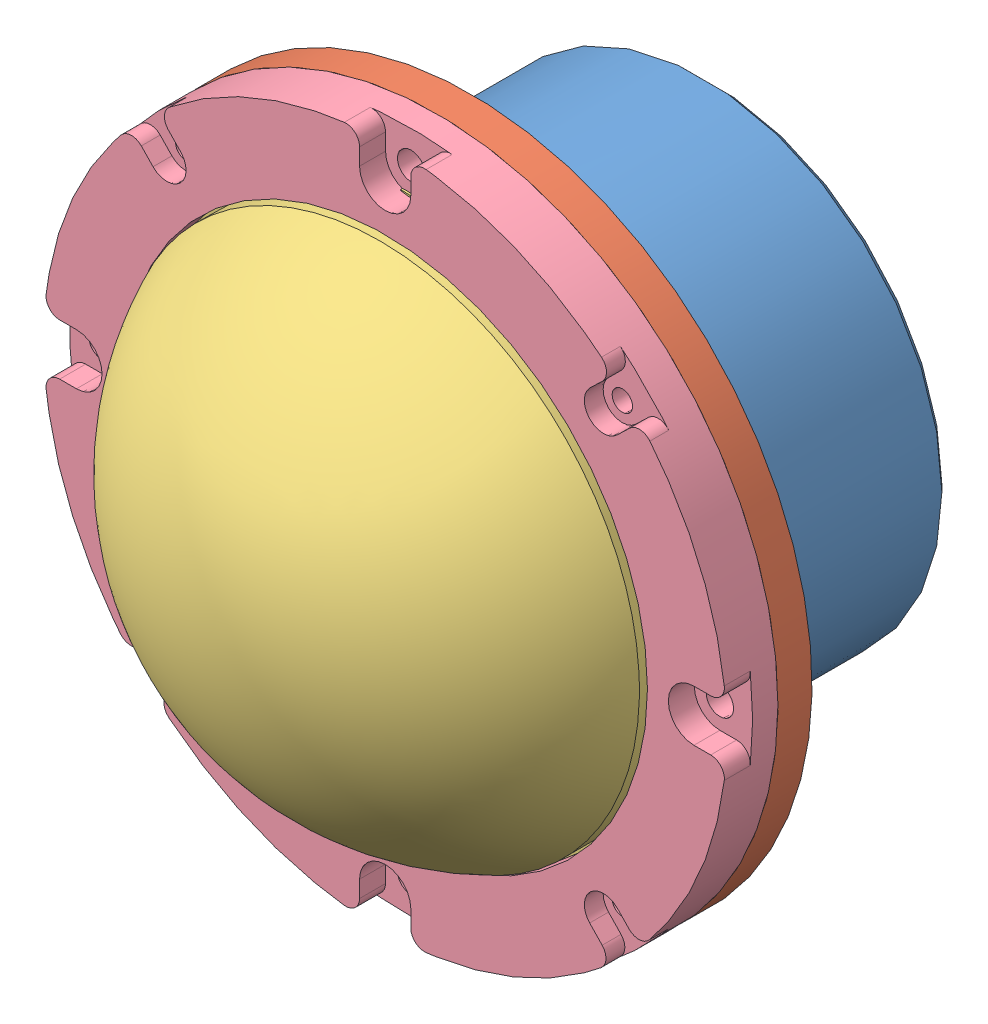
SolidWorks assembly Camera_Housing_Assy, configuration Default. Lengths in mm.
Overall size (165.96 165.96 96.7).
8 component instances, 8 part files, 16 mates.
Components (placement in the parent):
- Camera_Housing-1: Camera_Housing [Default] at (32.5452 69.9282 52.5859) size (88.9 88.9 44.45)
- auv01_camera_hull_front_cap_videoray-1: auv01_camera_hull_front_cap_videoray [Default] at (32.5452 69.9282 86.8759) x (-0.923728 -0.383049 0) z (0 0 -1) size (127 127 39.95)
- auv01_camera_dome_videoray-1: auv01_camera_dome_videoray [Default] at (32.5452 69.9282 86.8759) x (0 0 -1) z (0.999858 0.016854 0) size (41.84 106.05 101.6)
- auv01_camera_hull_lens_holder_dome_videoray-1: auv01_camera_hull_lens_holder_dome_videoray [Default] at (32.5452 69.9282 86.8759) size (127 127 9.53)
- Bottom Facing Camera Mount-1: Bottom Facing Camera Mount [Default] at (32.5237 69.99 112.2759) x (0.912173 0.409806 0) z (-0.409806 0.912173 0) size (50.35 69.85 50.16)
- Maybe Screw-1: Maybe Screw [Default] at (26.2129 84.0371 32.0119) x (-0.914921 0.403633 0) z (0.403633 0.914921 0) size (10 39.07 10)
- Test Camera (2)-1: Test Camera (2) [Default] at (32.5237 69.99 103.6399) x (0.912173 0.409806 0) z (0 0 1) size (23.11 22.86 43.81)
- Vertical Stopper-1: Vertical Stopper [Default] at (30.338 74.8551 74.1759) x (-0.409806 0.912173 0) z (-0.912173 -0.409806 0) size (29.72 10.16 10.67)
Mates (geometry in assembly coordinates):
- Coincident1: coincident: plane of Camera_Housing-1 through (32.5452 25.4782 80.5259) normal (0 0 1); plane of auv01_camera_hull_front_cap_videoray-1 through (-26.1115 45.6046 80.5259) normal (0 0 -1)
- Concentric1: concentric: cylinder of Camera_Housing-1 through (32.5452 69.9282 129.989) axis (0 0 1) radius 38.1; cylinder of auv01_camera_hull_front_cap_videoray-1 through (32.5452 69.9282 80.5259) axis (0 0 -1) radius 31.7246
- Coincident2: coincident: plane of auv01_camera_hull_front_cap_videoray-1 through (-26.1115 45.6046 86.8759) normal (0 0 1); plane of auv01_camera_dome_videoray-1 through (-13.4984 69.1521 86.8759) normal (0 0 -1)
- Concentric2: concentric: cylinder of auv01_camera_hull_front_cap_videoray-1 through (32.5452 69.9282 80.5259) axis (0 0 -1) radius 45.9994; circle of auv01_camera_dome_videoray-1
- Coincident4: coincident: plane of auv01_camera_hull_front_cap_videoray-1 through (-26.1115 45.6046 86.8759) normal (0 0 1); plane of auv01_camera_hull_lens_holder_dome_videoray-1 through (32.5452 69.9282 86.8759) normal (0 0 -1)
- Concentric4: concentric: cylinder of auv01_camera_hull_front_cap_videoray-1 through (32.5452 69.9282 80.5259) axis (0 0 -1) radius 63.5; cylinder of auv01_camera_hull_lens_holder_dome_videoray-1 through (32.5452 69.9282 93.2259) axis (0 0 1) radius 63.5
- Coincident5: coincident: plane of Camera_Housing-1 through (32.5452 33.0982 42.4259) normal (0 0 1); plane of Bottom Facing Camera Mount-1 through (32.5237 69.99 42.4259) normal (0 0 -1)
- Concentric7: concentric: cylinder of Camera_Housing-1 through (26.2129 84.0371 80.5269) axis (0 0 -1) radius 3.3; cylinder of Maybe Screw-1 through (26.2129 84.0371 71.0771) axis (0 0 -1) radius 3.3
- Coincident7: coincident: plane of Camera_Housing-1 through (32.5452 69.9282 36.0759) normal (0 0 -1); plane of Maybe Screw-1 through (26.2129 84.0371 36.0759) normal (0 0 1)
- Concentric10: concentric: cylinder of Camera_Housing-1 through (26.2129 84.0371 80.5269) axis (0 0 -1) radius 3.3; circle of Bottom Facing Camera Mount-1
- Width1: width: plane of Test Camera (2)-1 through (28.9828 60.672 114.1809) normal (0.409806 -0.912173 0); plane of Test Camera (2)-1 through (23.2058 73.5309 114.1809) normal (-0.409806 0.912173 0); plane of Bottom Facing Camera Mount-1 through (28.8233 60.2523 104.0209) normal (-0.409806 0.912173 0); plane of Bottom Facing Camera Mount-1 through (22.786 73.6904 104.0209) normal (0.409806 -0.912173 0)
- Width2: width: plane of Test Camera (2)-1 through (41.8417 66.449 114.1809) normal (0.912173 0.409806 0); plane of Test Camera (2)-1 through (28.9828 60.672 114.1809) normal (-0.912173 -0.409806 0); plane of Bottom Facing Camera Mount-1 through (42.2614 66.2895 104.0209) normal (-0.912173 -0.409806 0); plane of Bottom Facing Camera Mount-1 through (28.8233 60.2523 104.0209) normal (0.912173 0.409806 0)
- Coincident8: coincident: plane of Bottom Facing Camera Mount-1 through (32.5237 69.99 108.4659) normal (0 0 -1); plane of Test Camera (2)-1 through (41.2122 73.8934 108.4659) normal (0 0 1)
- Concentric11: concentric: cylinder of Maybe Screw-1 through (26.2129 84.0371 71.0771) axis (0 0 -1) radius 3.3; cylinder of Vertical Stopper-1 through (26.2129 84.0371 64.0159) axis (0 0 -1) radius 3.4016
- Coincident9: coincident: plane of Bottom Facing Camera Mount-1 through (32.5237 69.99 64.0159) normal (0 0 1); plane of Vertical Stopper-1 through (30.338 74.8551 64.0159) normal (0 0 -1)
- Parallel1: parallel: plane of Bottom Facing Camera Mount-1 through (39.8608 89.2975 70.3659) normal (0.912173 0.409806 0); plane of Vertical Stopper-1 through (41.2928 63.487 64.0159) normal (0.912173 0.409806 0)
